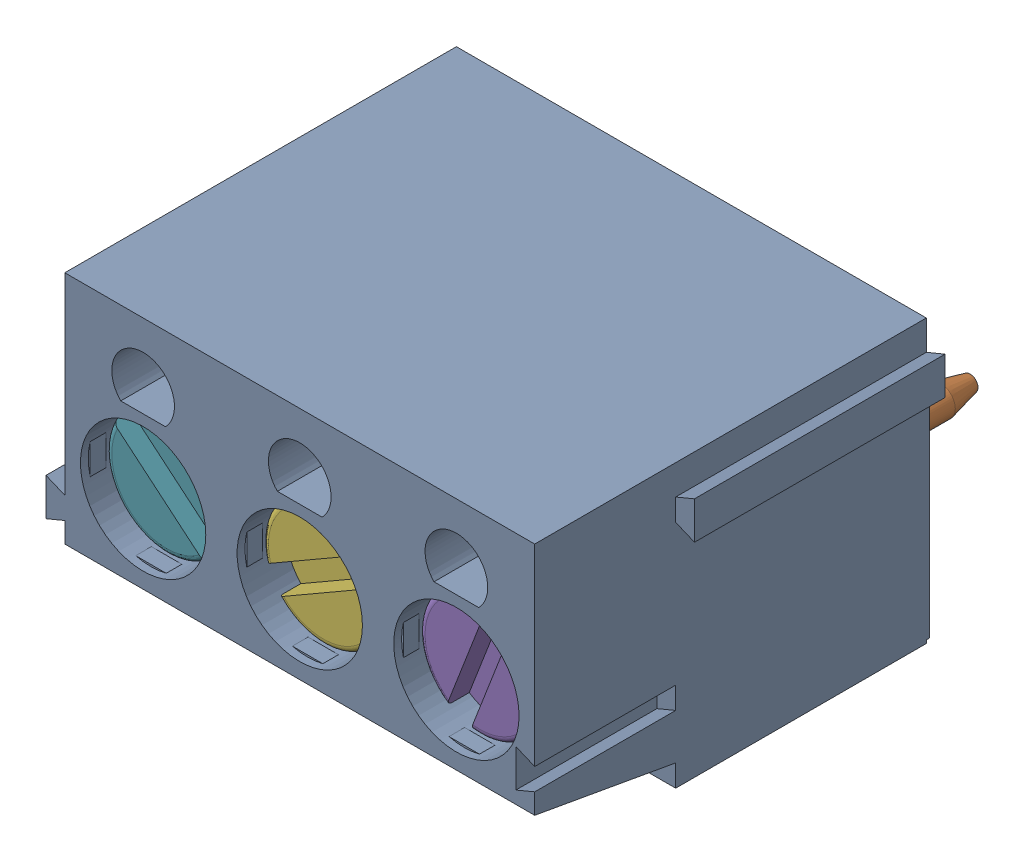
SolidWorks assembly 691101710003, configuration Default. Lengths in mm.
Overall size (16.2 9 16.4).
10 component instances, 4 part files, 0 mates.
Components (placement in the parent):
- 6911017100xx_1-1: 6911017100xx_1 [Default] at origin size (16.2 9 12.6)
- 6911017100xx_2-1: 6911017100xx_2 [Default] at (5 0 4) size (3.95 4 10.9)
- 6911017100xx_2-2: 6911017100xx_2 [Default] at (0 0 4) size (3.95 4 10.9)
- 6911017100xx_2-3: 6911017100xx_2 [Default] at (-5 0 4) size (3.95 4 10.9)
- 6911017100xx_3-1: 6911017100xx_3 [Default] at (5 0 11.75) x (0.93283 -0.360317 0) z (0 0 1) size (3.9 3.9 7.08)
- 6911017100xx_3-2: 6911017100xx_3 [Default] at (0 0 11.75) x (0.5 -0.866025 0) z (0 0 1) size (3.9 3.9 7.08)
- 6911017100xx_3-3: 6911017100xx_3 [Default] at (-5 0 11.75) x (-0.642788 -0.766044 0) z (0 0 1) size (3.9 3.9 7.08)
- 6911017100xx_4-1: 6911017100xx_4 [Default] at (5 0 7.2) size (3.95 5.03 4.22)
- 6911017100xx_4-2: 6911017100xx_4 [Default] at (0 0 7.2) size (3.95 5.03 4.22)
- 6911017100xx_4-3: 6911017100xx_4 [Default] at (-5 0 7.2) size (3.95 5.03 4.22)
